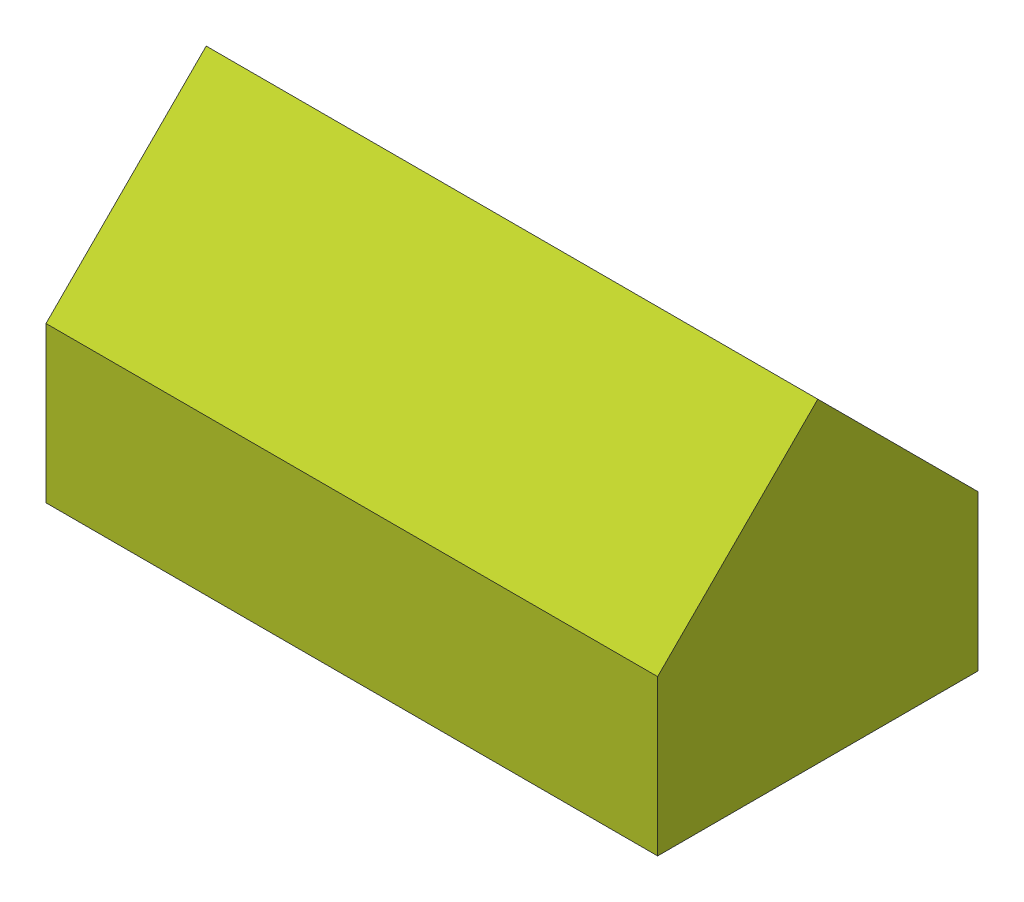
SolidWorks assembly GREENHOUSE, configuration Default. Lengths in mm.
Overall size (6300 3250.05 3300.1).
34 component instances, 9 part files, 100 mates.
Components (placement in the parent):
- base-1: base [默认] at (-50.3801 2866.8709 5337.6346) size (6050.8 1652.4 3050.8)
- floor-1: floor [默认] at (-50.3801 3019.2709 5337.6346) size (6000 25.4 3000)
- roof-1: roof [默认] at (25.8199 6044.6707 3837.6349) x (-1 0 0) z (0 0.707107 0.707107) size (152.4 2157.24 2157.24)
- roof-2: roof [默认] at (1000.4199 6044.6707 3837.6349) x (-1 0 0) z (0 0.707107 0.707107) size (152.4 2157.24 2157.24)
- roof-3: roof [默认] at (1975.0199 6044.8702 3837.8344) x (-1 0 0) z (0 0.707107 0.707107) size (152.4 2157.24 2157.24)
- roof-4: roof [默认] at (3924.2199 6044.6702 3837.6344) x (-1 0 0) z (0 0.707107 0.707107) size (152.4 2157.24 2157.24)
- roof-5: roof [默认] at (2949.6199 6044.6702 3837.6344) x (-1 0 0) z (0 0.707107 0.707107) size (152.4 2157.24 2157.24)
- roof-6: roof [默认] at (4898.8199 6044.6697 3837.6349) x (-1 0 0) z (0 0.707107 0.707107) size (152.4 2157.24 2157.24)
- roof-7: roof [默认] at (5873.4199 6044.6692 3837.6344) x (-1 0 0) z (0 0.707107 0.707107) size (152.4 2157.24 2157.24)
- panel-1: panel [默认] at (5985.0199 2976.7034 6689.4942) x (0 0 1) z (0 -1 0) size (1000 10 1600)
- panel-2: panel [默认] at (5985.0199 2976.7034 5689.4942) x (0 0 1) z (0 -1 0) size (1000 10 1600)
- panel-3: panel [默认] at (5975.0199 4461.8385 4689.4942) x (0 0 1) z (0 1 0) size (1000 10 1600)
- panel-4: panel [默认] at (7307.728 4461.8385 5373.0346) x (1 0 0) z (0 1 0) size (1000 10 1600)
- panel-5: panel [默认] at (6307.728 2976.7034 5363.0346) x (1 0 0) z (0 -1 0) size (1000 10 1600)
- panel-6: panel [默认] at (2307.728 2976.7034 2302.2346) x (1 0 0) z (0 -1 0) size (1000 10 1600)
- panel-7: panel [默认] at (5307.728 4461.8385 5373.0346) x (1 0 0) z (0 1 0) size (1000 10 1600)
- panel-8: panel [默认] at (3307.728 2976.7034 2302.4346) x (1 0 0) z (0 -1 0) size (1000 10 1600)
- panel-9: panel [默认] at (-75.7801 4461.8385 1973.278) x (0 0 -1) z (0 1 0) size (1000 10 1600)
- panel-10: panel [默认] at (3307.728 2976.7034 5363.0346) x (1 0 0) z (0 -1 0) size (1000 10 1600)
- panel-11: panel [默认] at (-75.7801 4461.8385 2973.278) x (0 0 -1) z (0 1 0) size (1000 10 1600)
- panel-12: panel [默认] at (2307.728 4461.8385 5373.0346) x (1 0 0) z (0 1 0) size (1000 10 1600)
- panel-13: panel [默认] at (-75.7801 4461.8385 973.278) x (0 0 -1) z (0 1 0) size (1000 10 1600)
- panel-15: panel [默认] at (4307.728 2976.7034 5363.0346) x (1 0 0) z (0 -1 0) size (1000 10 1600)
- panel-16: panel [默认] at (5307.728 2976.7034 2302.2346) x (1 0 0) z (0 -1 0) size (1000 10 1600)
- panel-17: panel [默认] at (4307.728 2976.7034 2302.4346) x (1 0 0) z (0 -1 0) size (1000 10 1600)
- panel-18: panel [默认] at (6307.728 2976.7034 2302.2346) x (1 0 0) z (0 -1 0) size (1000 10 1600)
- panel-19: panel [默认] at (7307.728 2976.7034 2302.2346) x (1 0 0) z (0 -1 0) size (1000 10 1600)
- panel2-1: panel2 [默认] at (5949.6199 4519.2709 5333.0341) size (10 1500 3000)
- panel2-2: panel2 [默认] at (-60.3801 4519.2709 5338.9771) size (10 1500 3000)
- panel3-1: panel3 [默认] at (-50.3801 4551.742 2330.5641) x (0 -0.707107 0.707107) z (-1 0 0) size (10 2121.32 6000)
- panel3-2: panel3 [默认] at (5949.6199 6035.0723 3847.2333) x (0 0.707107 0.707107) z (1 0 0) size (10 2121.32 6000)
- extra film-1: extra film [默认] at (-108.0925 2866.8712 5364.6437) x (0 0 -1) z (1 0 0) size (3300.1 3250.05 6300)
- DEMO PLANT-1: DEMO PLANT [默认] at (1528.157 3044.6709 2867.6069) size (567.95 500 567.95)
- PLANT-1: PLANT [默认] at (1504.6539 3544.6709 2854.2155) size (397.54 528.59 50)
Mates (geometry in assembly coordinates):
- 重合1: coincident anti-aligned: plane of base-1 through (-50.3801 3019.2709 5337.6346) normal (0 1 0); plane of floor-1 through (-50.3801 3019.2709 5337.6346) normal (0 -1 0)
- 重合2: coincident anti-aligned: plane of base-1 through (5949.6199 4519.2709 3286.8346) normal (-1 0 0); plane of floor-1 through (5949.6199 3044.6709 5337.6346) normal (1 0 0)
- 重合3: coincident anti-aligned: plane of base-1 through (4822.6199 4519.2709 2337.6346) normal (0 0 1); plane of floor-1 through (-50.3801 3044.6709 2337.6346) normal (0 0 -1)
- 重合6: coincident anti-aligned: plane of base-1 through (-50.3801 4519.2709 5337.6346) normal (0 1 0); plane of roof-1 through (25.8199 4519.2709 3837.6349) normal (0 -1 0)
- 平行4: parallel aligned: plane of floor-1 through (-50.3801 3044.6709 5337.6346) normal (0 1 0); plane of roof-7 through (5873.4199 4544.6695 3837.6344) normal (0 1 0)
- 重合17: coincident anti-aligned: plane of base-1 through (-50.3801 4519.2709 5337.6346) normal (0 0 -1); plane of roof-1 through (102.0199 4519.2709 5337.6346) normal (0 0 1)
- 重合19: coincident aligned: plane of base-1 through (102.0199 4519.2709 5337.6346) normal (1 0 0); plane of roof-1 through (102.0199 6044.6707 3837.6349) normal (1 0 0)
- 平行6: parallel aligned: plane of roof-1 through (102.0199 6044.6707 3837.6349) normal (0 0.707107 0.707107); plane of roof-2 through (1076.6199 6044.6707 3837.6349) normal (0 0.707107 0.707107)
- 重合25: coincident anti-aligned: plane of base-1 through (-50.3801 4519.2709 5337.6346) normal (0 1 0); plane of roof-2 through (1000.4199 4519.2709 3837.6349) normal (0 -1 0)
- 重合26: coincident aligned: plane of roof-1 through (102.0199 4519.2709 5337.6346) normal (0 0 1); plane of roof-2 through (1076.6199 4519.2709 5337.6346) normal (0 0 1)
- 重合27: coincident aligned: plane of roof-1 through (102.0199 6044.6707 3837.6349) normal (0 0.707107 0.707107); plane of roof-2 through (1076.6199 6044.6707 3837.6349) normal (0 0.707107 0.707107)
- 重合28: coincident aligned: plane of roof-1 through (102.0199 6044.6707 3837.6349) normal (0 0.707107 -0.707107); plane of roof-2 through (1076.6199 6044.6707 3837.6349) normal (0 0.707107 -0.707107)
- 重合29: coincident anti-aligned: plane of base-1 through (1898.8199 4519.2709 2337.8346) normal (0 0 1); plane of roof-3 through (2051.2199 4519.4704 2337.8346) normal (0 0 -1)
- 重合30: coincident aligned: plane of roof-2 through (1076.6199 6044.6707 3837.6349) normal (0 0.707107 -0.707107); plane of roof-3 through (2051.2199 6044.8702 3837.8344) normal (0 0.707107 -0.707107)
- 重合31: coincident aligned: plane of base-1 through (1898.8199 4519.2709 2337.8346) normal (-1 0 0); plane of roof-3 through (1898.8199 6044.8702 3837.8344) normal (-1 0 0)
- 重合32: coincident anti-aligned: plane of base-1 through (2873.4199 4519.2709 2337.6346) normal (0 0 1); plane of roof-5 through (3025.8199 4519.2704 2337.6346) normal (0 0 -1)
- 重合33: coincident aligned: plane of roof-3 through (2051.2199 6044.8702 3837.8344) normal (0 0.707107 -0.707107); plane of roof-5 through (3025.8199 6044.6702 3837.6344) normal (0 0.707107 -0.707107)
- 重合34: coincident aligned: plane of base-1 through (2873.4199 4519.2709 2337.6346) normal (-1 0 0); plane of roof-5 through (2873.4199 6044.6702 3837.6344) normal (-1 0 0)
- 重合35: coincident anti-aligned: plane of base-1 through (3848.0199 4519.2709 2337.6346) normal (0 0 1); plane of roof-4 through (4000.4199 4519.2704 2337.6346) normal (0 0 -1)
- 重合36: coincident aligned: plane of roof-4 through (4000.4199 6044.6702 3837.6344) normal (0 0.707107 -0.707107); plane of roof-5 through (3025.8199 6044.6702 3837.6344) normal (0 0.707107 -0.707107)
- 重合37: coincident aligned: plane of base-1 through (3848.0199 4519.2709 2337.6346) normal (-1 0 0); plane of roof-4 through (3848.0199 6044.6702 3837.6344) normal (-1 0 0)
- 重合38: coincident anti-aligned: plane of base-1 through (4822.6199 4519.2709 5337.6346) normal (0 0 -1); plane of roof-6 through (4975.0199 4519.27 5337.6346) normal (0 0 1)
- 重合39: coincident aligned: plane of roof-4 through (4000.4199 6044.6702 3837.6344) normal (0 0.707107 0.707107); plane of roof-6 through (4975.0199 6044.6697 3837.6349) normal (0 0.707107 0.707107)
- 重合40: coincident aligned: plane of base-1 through (4975.0199 4519.2709 5337.6346) normal (1 0 0); plane of roof-6 through (4975.0199 6044.6697 3837.6349) normal (1 0 0)
- 重合43: coincident anti-aligned: plane of base-1 through (5797.2199 4519.2709 2337.6346) normal (0 0 1); plane of roof-7 through (5949.6199 4519.2695 2337.6346) normal (0 0 -1)
- 重合44: coincident aligned: plane of roof-6 through (4975.0199 6044.6697 3837.6349) normal (0 0.707107 -0.707107); plane of roof-7 through (5949.6199 6044.6692 3837.6344) normal (0 0.707107 -0.707107)
- 重合45: coincident aligned: plane of base-1 through (5949.6199 3019.2709 5337.6346) normal (1 0 0); plane of roof-7 through (5949.6199 6044.6692 3837.6344) normal (1 0 0)
- 平行8: parallel anti-aligned: plane of base-1 through (5975.0199 3019.2709 5337.6346) normal (1 0 0); plane of panel-1 through (5975.0199 2976.7034 6689.4942) normal (-1 0 0)
- 重合47: coincident aligned: plane of base-1 through (5975.0199 4519.2709 5331.3861) normal (0 0 1); plane of panel-1 through (5975.0199 4519.2709 5331.3861) normal (0 0 1)
- 重合48: coincident aligned: plane of base-1 through (-50.3801 4519.2709 5337.6346) normal (0 1 0); plane of panel-1 through (5975.0199 4519.2709 4331.3861) normal (0 1 0)
- 重合49: coincident anti-aligned: plane of base-1 through (5975.0199 3019.2709 5337.6346) normal (1 0 0); plane of panel-1 through (5975.0199 2976.7034 6689.4942) normal (-1 0 0)
- 重合50: coincident aligned: plane of panel-1 through (5985.0199 2976.7034 6689.4942) normal (1 0 0); plane of panel-2 through (5985.0199 2976.7034 5689.4942) normal (1 0 0)
- 重合52: coincident anti-aligned: plane of panel-1 through (5975.0199 4519.2709 4331.3861) normal (0 0 -1); plane of panel-2 through (5975.0199 4519.2709 4331.3861) normal (0 0 1)
- 重合53: coincident aligned: plane of panel-1 through (5975.0199 4519.2709 4331.3861) normal (0 1 0); plane of panel-2 through (5975.0199 4519.2709 3331.3861) normal (0 1 0)
- 重合54: coincident aligned: plane of panel-2 through (5985.0199 2976.7034 5689.4942) normal (1 0 0); plane of panel-3 through (5985.0199 4461.8385 4689.4942) normal (1 0 0)
- 重合55: coincident anti-aligned: plane of panel-2 through (5975.0199 4519.2709 3331.3861) normal (0 0 -1); plane of panel-3 through (5985.0199 2919.2709 3331.3861) normal (0 0 1)
- 重合56: coincident aligned: plane of panel-2 through (5975.0199 4519.2709 3331.3861) normal (0 1 0); plane of panel-3 through (5985.0199 4519.2709 2331.3861) normal (0 1 0)
- 重合57: coincident anti-aligned: plane of base-1 through (5797.2199 4519.2709 5363.0346) normal (0 0 1); plane of panel-4 through (7307.728 4461.8385 5363.0346) normal (0 0 -1)
- 重合58: coincident aligned: plane of base-1 through (5949.6199 3019.2709 5337.6346) normal (1 0 0); plane of panel-4 through (5949.6199 2919.2709 5363.0346) normal (1 0 0)
- 重合59: coincident aligned: plane of base-1 through (-50.3801 4519.2709 5337.6346) normal (0 1 0); plane of panel-4 through (4949.6199 4519.2709 5363.0346) normal (0 1 0)
- 重合60: coincident aligned: plane of panel-4 through (7307.728 4461.8385 5373.0346) normal (0 0 1); plane of panel-5 through (6307.728 2976.7034 5373.0346) normal (0 0 1)
- 重合61: coincident anti-aligned: plane of panel-4 through (4949.6199 2919.2709 5363.0346) normal (-1 0 0); plane of panel-5 through (4949.6199 4519.2709 5373.0346) normal (1 0 0)
- 重合62: coincident aligned: plane of panel-4 through (4949.6199 4519.2709 5363.0346) normal (0 1 0); plane of panel-5 through (3949.6199 4519.2709 5373.0346) normal (0 1 0)
- 重合64: coincident aligned: plane of panel-5 through (6307.728 2976.7034 5373.0346) normal (0 0 1); plane of panel-7 through (5307.728 4461.8385 5373.0346) normal (0 0 1)
- 重合65: coincident anti-aligned: plane of panel-5 through (3949.6199 4519.2709 5373.0346) normal (-1 0 0); plane of panel-7 through (3949.6199 2919.2709 5363.0346) normal (1 0 0)
- 重合66: coincident aligned: plane of panel-5 through (3949.6199 4519.2709 5373.0346) normal (0 1 0); plane of panel-7 through (2949.6199 4519.2709 5363.0346) normal (0 1 0)
- 重合67: coincident aligned: plane of panel-7 through (5307.728 4461.8385 5373.0346) normal (0 0 1); plane of panel-15 through (4307.728 2976.7034 5373.0346) normal (0 0 1)
- 重合68: coincident anti-aligned: plane of panel-7 through (2949.6199 2919.2709 5363.0346) normal (-1 0 0); plane of panel-15 through (2949.6199 4519.2709 5373.0346) normal (1 0 0)
- 重合69: coincident: plane of panel-7 through (2949.6199 4519.2709 5363.0346) normal (0 1 0); line of panel-15 through (2949.6199 4519.2709 5373.0346) axis (-1 0 0)
- 重合70: coincident aligned: plane of panel-10 through (3307.728 2976.7034 5373.0346) normal (0 0 1); plane of panel-15 through (4307.728 2976.7034 5373.0346) normal (0 0 1)
- 重合71: coincident anti-aligned: plane of panel-10 through (1949.6199 4519.2709 5373.0346) normal (1 0 0); plane of panel-15 through (1949.6199 4519.2709 5373.0346) normal (-1 0 0)
- 重合72: coincident: line of panel-10 through (1949.6199 4519.2709 5373.0346) axis (-1 0 0); plane of panel-15 through (1949.6199 4519.2709 5373.0346) normal (0 1 0)
- 重合73: coincident aligned: plane of panel-10 through (3307.728 2976.7034 5373.0346) normal (0 0 1); plane of panel-12 through (2307.728 4461.8385 5373.0346) normal (0 0 1)
- 重合74: coincident anti-aligned: plane of panel-10 through (949.6199 4519.2709 5373.0346) normal (-1 0 0); plane of panel-12 through (949.6199 2919.2709 5363.0346) normal (1 0 0)
- 重合75: coincident aligned: plane of panel-10 through (949.6199 4519.2709 5373.0346) normal (0 1 0); plane of panel-12 through (-50.3801 4519.2709 5363.0346) normal (0 1 0)
- 重合76: coincident anti-aligned: plane of base-1 through (-75.7801 3019.2709 5337.6346) normal (-1 0 0); plane of panel-11 through (-75.7801 4461.8385 2973.278) normal (1 0 0)
- 重合77: coincident aligned: plane of base-1 through (-75.7801 4519.2709 5331.3861) normal (0 0 1); plane of panel-11 through (-85.7801 2919.2709 5331.3861) normal (0 0 1)
- 重合78: coincident aligned: plane of base-1 through (-50.3801 4519.2709 5337.6346) normal (0 1 0); plane of panel-11 through (-85.7801 4519.2709 5331.3861) normal (0 1 0)
- 重合80: coincident aligned: plane of panel-9 through (-85.7801 4461.8385 1973.278) normal (-1 0 0); plane of panel-11 through (-85.7801 4461.8385 2973.278) normal (-1 0 0)
- 重合81: coincident anti-aligned: plane of panel-9 through (-85.7801 2919.2709 4331.3861) normal (0 0 1); plane of panel-11 through (-85.7801 2919.2709 4331.3861) normal (0 0 -1)
- 重合82: coincident aligned: plane of panel-9 through (-85.7801 4519.2709 4331.3861) normal (0 1 0); plane of panel-11 through (-85.7801 4519.2709 5331.3861) normal (0 1 0)
- 重合83: coincident aligned: plane of panel-9 through (-85.7801 4461.8385 1973.278) normal (-1 0 0); plane of panel-13 through (-85.7801 4461.8385 973.278) normal (-1 0 0)
- 重合84: coincident anti-aligned: plane of panel-9 through (-85.7801 2919.2709 3331.3861) normal (0 0 -1); plane of panel-13 through (-85.7801 2919.2709 3331.3861) normal (0 0 1)
- 重合85: coincident aligned: plane of panel-9 through (-85.7801 4519.2709 4331.3861) normal (0 1 0); plane of panel-13 through (-85.7801 4519.2709 3331.3861) normal (0 1 0)
- 重合86: coincident anti-aligned: plane of base-1 through (-50.3801 4519.2709 2312.2346) normal (0 0 -1); plane of panel-6 through (2307.728 2976.7034 2312.2346) normal (0 0 1)
- 重合87: coincident aligned: plane of base-1 through (-50.3801 3019.2709 5337.6346) normal (-1 0 0); plane of panel-6 through (-50.3801 4519.2709 2312.2346) normal (-1 0 0)
- 重合88: coincident aligned: plane of base-1 through (-50.3801 4519.2709 5337.6346) normal (0 1 0); plane of panel-6 through (-50.3801 4519.2709 2312.2346) normal (0 1 0)
- 重合90: coincident anti-aligned: plane of panel-6 through (949.6199 4519.2709 2312.2346) normal (1 0 0); plane of panel-8 through (949.6199 4519.2709 2312.4346) normal (-1 0 0)
- 重合91: coincident aligned: plane of panel-6 through (-50.3801 4519.2709 2312.2346) normal (0 1 0); plane of panel-8 through (949.6199 4519.2709 2312.4346) normal (0 1 0)
- 重合92: coincident anti-aligned: plane of base-1 through (924.2199 4519.2709 2312.4346) normal (0 0 -1); plane of panel-8 through (3307.728 2976.7034 2312.4346) normal (0 0 1)
- 重合96: coincident aligned: plane of panel-8 through (949.6199 4519.2709 2312.4346) normal (0 1 0); plane of panel-17 through (1949.6199 4519.2709 2312.4346) normal (0 1 0)
- 重合97: coincident anti-aligned: plane of panel-8 through (1949.6199 4519.2709 2312.4346) normal (1 0 0); plane of panel-17 through (1949.6199 4519.2709 2312.4346) normal (-1 0 0)
- 重合98: coincident anti-aligned: plane of base-1 through (1898.8199 4519.2709 2312.4346) normal (0 0 -1); plane of panel-17 through (4307.728 2976.7034 2312.4346) normal (0 0 1)
- 重合100: coincident aligned: plane of panel-16 through (2949.6199 4519.2709 2312.2346) normal (0 1 0); plane of panel-17 through (1949.6199 4519.2709 2312.4346) normal (0 1 0)
- 重合103: coincident anti-aligned: plane of base-1 through (2873.4199 4519.2709 2312.2346) normal (0 0 -1); plane of panel-16 through (5307.728 2976.7034 2312.2346) normal (0 0 1)
- 重合104: coincident anti-aligned: plane of panel-16 through (2949.6199 4519.2709 2312.2346) normal (-1 0 0); plane of panel-17 through (2949.6199 4519.2709 2312.4346) normal (1 0 0)
- 重合105: coincident aligned: plane of panel-16 through (5307.728 2976.7034 2302.2346) normal (0 0 -1); plane of panel-18 through (6307.728 2976.7034 2302.2346) normal (0 0 -1)
- 重合106: coincident anti-aligned: plane of panel-16 through (3949.6199 4519.2709 2312.2346) normal (1 0 0); plane of panel-18 through (3949.6199 4519.2709 2312.2346) normal (-1 0 0)
- 重合107: coincident aligned: plane of panel-16 through (2949.6199 4519.2709 2312.2346) normal (0 1 0); plane of panel-18 through (3949.6199 4519.2709 2312.2346) normal (0 1 0)
- 重合108: coincident aligned: plane of panel-18 through (6307.728 2976.7034 2302.2346) normal (0 0 -1); plane of panel-19 through (7307.728 2976.7034 2302.2346) normal (0 0 -1)
- 重合109: coincident anti-aligned: plane of panel-18 through (4949.6199 4519.2709 2312.2346) normal (1 0 0); plane of panel-19 through (4949.6199 4519.2709 2312.2346) normal (-1 0 0)
- 重合110: coincident aligned: plane of panel-18 through (3949.6199 4519.2709 2312.2346) normal (0 1 0); plane of panel-19 through (4949.6199 4519.2709 2312.2346) normal (0 1 0)
- 重合111: coincident anti-aligned: plane of roof-7 through (5949.6199 6044.6692 3837.6344) normal (1 0 0); plane of panel2-1 through (5949.6199 4519.2709 5333.0341) normal (-1 0 0)
- 重合112: coincident anti-aligned: plane of panel-1 through (5975.0199 4519.2709 4331.3861) normal (0 1 0); plane of panel2-1 through (5959.6199 4519.2709 5333.0341) normal (0 -1 0)
- 平行14: parallel aligned: line of roof-7 through (5949.6199 6044.6692 3837.6344) axis (-1 0 0); line of panel2-1 through (5959.6199 6019.2709 3833.034) axis (-1 0 0)
- 锁定1: lock: unknown of roof-7; unknown of panel2-1
- 重合123: coincident anti-aligned: plane of roof-1 through (-50.3801 6044.6707 3837.6349) normal (-1 0 0); plane of panel2-2 through (-50.3801 4519.2709 5338.9771) normal (1 0 0)
- 重合124: coincident anti-aligned: plane of panel-13 through (-85.7801 4519.2709 3331.3861) normal (0 1 0); plane of panel2-2 through (-50.3801 4519.2709 5338.9771) normal (0 -1 0)
- 锁定2: lock: unknown of roof-1; unknown of panel2-2
- 重合126: coincident anti-aligned: plane of roof-4 through (4000.4199 6044.6702 3837.6344) normal (0 0.707107 -0.707107); plane of panel3-1 through (-50.3801 4544.6709 2337.6351) normal (0 -0.707107 0.707107)
- 重合127: coincident aligned: plane of roof-7 through (5949.6199 6044.6692 3837.6344) normal (1 0 0); plane of panel3-1 through (5949.6199 4544.6709 2337.6351) normal (1 0 0)
- 重合128: coincident anti-aligned: line of roof-1 through (102.0199 4544.6709 2337.6351) axis (-1 0 0); line of panel3-1 through (-50.3801 4544.6709 2337.6351) axis (1 0 0)
- 重合129: coincident anti-aligned: plane of roof-1 through (102.0199 6044.6707 3837.6349) normal (0 0.707107 0.707107); plane of panel3-2 through (5949.6199 6035.0723 3847.2333) normal (0 -0.707107 -0.707107)
- 对称3: symmetric aligned: plane of roof-1 through (-50.3801 6044.6707 3837.6349) normal (-1 0 0); plane of panel3-2 through (-50.3801 6042.1434 3854.3043) normal (-1 0 0); plane of panel3-2 through (5949.6199 6042.1434 3854.3043) normal (0 0.707107 0.707107)
- 锁定3: lock: unknown of panel2-2; unknown of panel3-2
- 重合136: coincident aligned: plane of base-1 through (924.2199 4519.2709 5337.4346) normal (-1 0 0); plane of roof-2 through (924.2199 6044.6707 3837.6349) normal (-1 0 0)
- 重合137: coincident aligned: plane of base-1 through (-50.3801 2866.8709 5337.6346) normal (0 -1 0); plane of extra film-1 through (5991.9075 2866.8709 2214.6437) normal (0 -1 0)
- 重合138: coincident anti-aligned: plane of floor-1 through (-50.3801 3044.6709 5337.6346) normal (0 1 0); plane of DEMO PLANT-1 through (1504.6539 3044.6709 2854.2155) normal (0 -1 0)
- 同心1: concentric aligned: circle of DEMO PLANT-1; circle of PLANT-1
- 重合139: coincident aligned: plane of DEMO PLANT-1 through (1504.6539 3544.6709 2854.2155) normal (0 1 0); circle of PLANT-1
